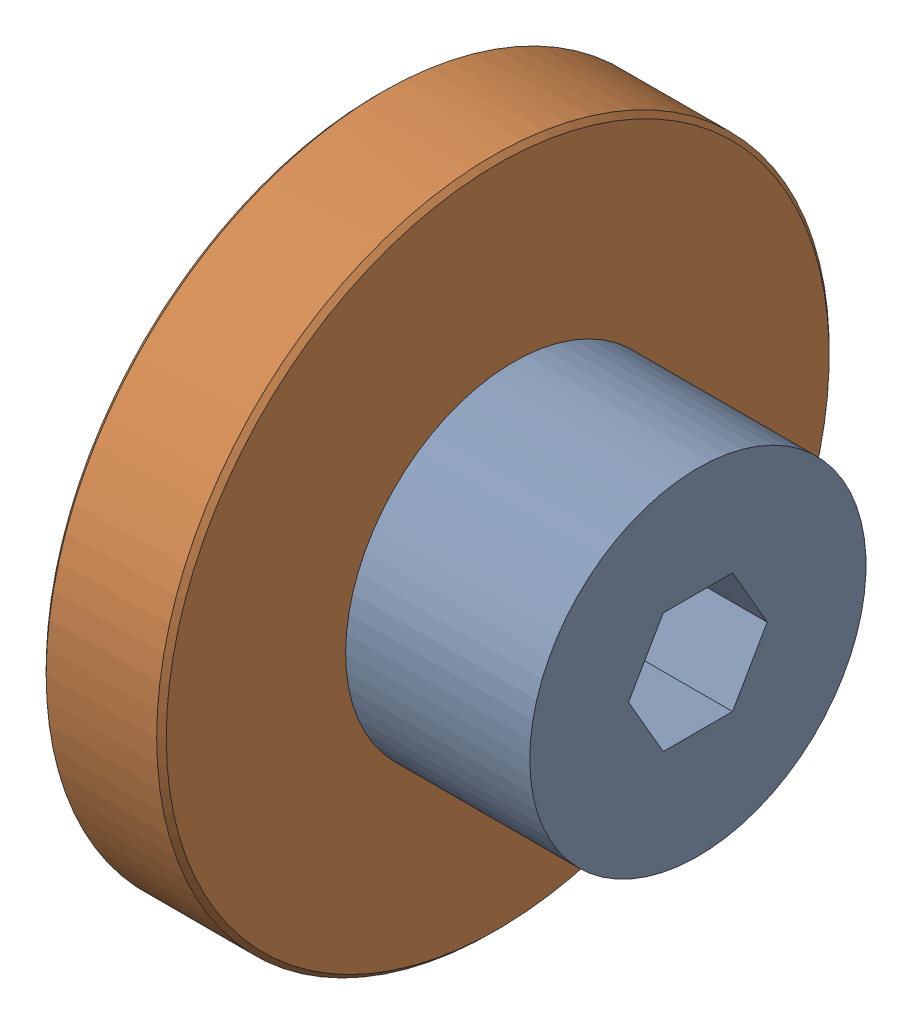
SolidWorks assembly ws_cluster_2, configuration Default. Lengths in mm.
Overall size (25.4 53.34 53.34).
2 component instances, 2 part files, 0 mates.
Components (placement in the parent):
- AM_19t_ws_cluster_gear-1: AM_19t_ws_cluster_gear [Default] at (824.1831 288.106 0) x (0 0 1) z (-1 0 0) size (26.67 26.67 15.24)
- 40t_ws_output_gear_revb-1: 40t_ws_output_gear_revb [Default] at (1645.8206 73.8733 0) x (-1 0 0) z (0 0 -1) size (10.43 53.34 53.34)
